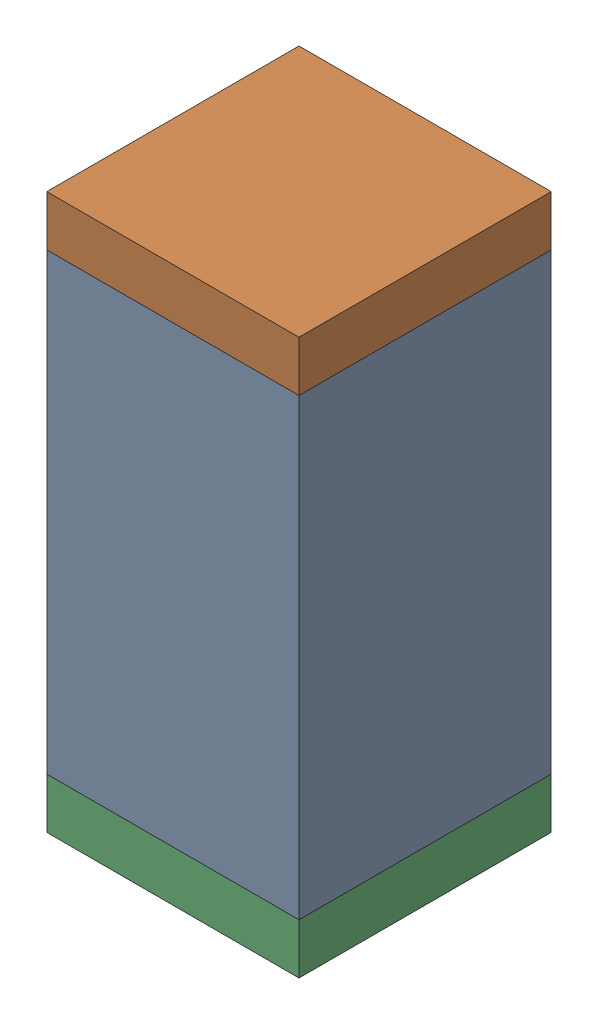
SolidWorks assembly C93, configuration Default. Lengths in mm.
Overall size (0.5 1.1 0.5).
6 component instances, 2 part files, 0 mates.
Components (placement in the parent):
- 791586336-1: 791586336 [Default] at (119.7 66.8 0) size (0.5 0.9 0.5)
  - Extruded_8-1: Extruded_8 [Default] at origin size (0.5 0.9 0.5)
- 810157360-1: 810157360 [Default] at (119.7 67.3 0) size (0.5 0.1 0.5)
  - Extruded_9-1: Extruded_9 [Default] at origin size (0.5 0.1 0.5)
- 810157360-2: 810157360 [Default] at (119.7 66.3 0) size (0.5 0.1 0.5)
  - Extruded_9-1: Extruded_9 [Default] at origin size (0.5 0.1 0.5)
